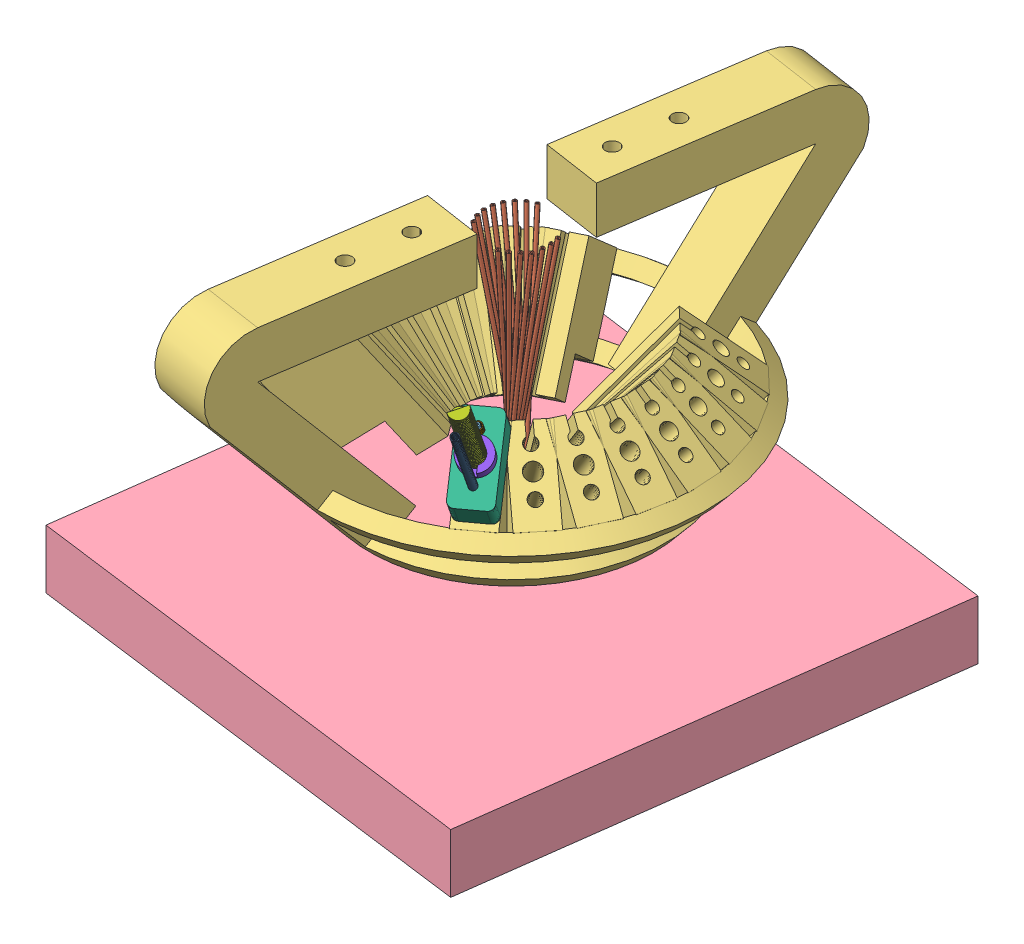
SolidWorks assembly DriveAssembling_Step2, configuration Default. Lengths in mm.
Overall size (54.17 33.57 54.17).
25 component instances, 10 part files, 11 mates.
Components (placement in the parent):
- MainCanula-1: MainCanula [Default] at (-0.3826 2 0.0965) size (2.41 8 2.41)
- 30g_slightly_curved-17: 30g_slightly_curved [Default] at (-0.1896 12 0.6153) x (0.96591 0 0.25888) z (-0.25888 0 0.96591) size (2.93 29.8 0.32)
- 30g_slightly_curved-18: 30g_slightly_curved [Default] at (-0.1582 12 0.527) x (1 0 0.000063) z (-0.000063 0 1) size (2.93 29.8 0.32)
- 30g_slightly_curved-19: 30g_slightly_curved [Default] at (-0.0165 12 0.55) x (0.965942 0 -0.258759) z (0.258759 0 0.965942) size (2.93 29.8 0.32)
- 30g_slightly_curved-20: 30g_slightly_curved [Default] at (0.1264 12 0.5355) x (0.866057 0 -0.499946) z (0.499946 0 0.866057) size (2.93 29.8 0.32)
- 30g_slightly_curved-22: 30g_slightly_curved [Default] at (0.5355 12 -0.1264) x (-0.499946 0 -0.866057) z (0.866057 0 -0.499946) size (2.93 29.8 0.32)
- 30g_slightly_curved-23: 30g_slightly_curved [Default] at (0.4845 12 -0.2607) x (-0.707062 0 -0.707151) z (0.707151 0 -0.707062) size (2.93 29.8 0.32)
- 30g_slightly_curved-24: 30g_slightly_curved [Default] at (0.4005 12 -0.3772) x (-0.865994 0 -0.500054) z (0.500054 0 -0.865994) size (2.93 29.8 0.32)
- 30g_slightly_curved-25: 30g_slightly_curved [Default] at (0.2892 12 -0.468) x (-0.96591 0 -0.25888) z (0.25888 0 -0.96591) size (2.93 29.8 0.32)
- 30g_slightly_curved-26: 30g_slightly_curved [Default] at (0.1582 12 -0.527) x (-1 0 -0.000063) z (0.000063 0 -1) size (2.93 29.8 0.32)
- 30g_slightly_curved-27: 30g_slightly_curved [Default] at (0.0165 12 -0.55) x (-0.965942 0 0.258759) z (-0.258759 0 -0.965942) size (2.93 29.8 0.32)
- 30g_slightly_curved-28: 30g_slightly_curved [Default] at (-0.1264 12 -0.5355) x (-0.866057 0 0.499946) z (-0.499946 0 -0.866057) size (2.93 29.8 0.32)
- 30g_slightly_curved-29: 30g_slightly_curved [Default] at (-0.2607 12 -0.4845) x (-0.707151 0 0.707062) z (-0.707062 0 -0.707151) size (2.93 29.8 0.32)
- 30g_slightly_curved-30: 30g_slightly_curved [Default] at (-0.5355 12 0.1264) x (0.499946 0 0.866057) z (-0.866057 0 0.499946) size (2.93 29.8 0.32)
- 30g_slightly_curved-31: 30g_slightly_curved [Default] at (-0.4845 12 0.2607) x (0.707062 0 0.707151) z (-0.707151 0 0.707062) size (2.93 29.8 0.32)
- 30g_slightly_curved-32: 30g_slightly_curved [Default] at (-0.4005 12 0.3772) x (0.865994 0 0.500054) z (-0.500054 0 0.865994) size (2.93 29.8 0.32)
- drive_circle_16-1: drive_circle_16 [Default] at (-0.3826 8.1312 0.0965) x (0.594671 0 0.803969) z (-0.803969 0 0.594671) size (38.73 24.23 38.73)
- SingleCanulaBase-1: SingleCanulaBase [Default] at (-0.3826 0 0.0965) x (0.991445 0 0.130526) z (-0.130526 0 0.991445) size (40 5 40)
- 30g_curved_long-18: 30g_curved_long [Default] at (-0.4481 8 0.0079) x (0.594671 0 0.803969) z (-0.803969 0 0.594671) size (14.22 24.96 0.32)
- ShuttleAssembly-1: ShuttleAssembly [Default] at (3.0743 17.254 14.0561) x (-0.455545 0.642788 -0.615876) z (0.803969 0 -0.594671) size (6.5 25.22 3)
  - drive_shuttle-1: drive_shuttle [Default] at (2.5582 1.9761 5.5221) size (6.5 3 3)
  - drive_threaded_rod_25mm-1: drive_threaded_rod_25mm [Default] at (2.5582 -8.5786 5.5221) x (0.813094 0 0.582132) z (-0.582132 0 0.813094) size (1.64 25.22 1.64)
  - Grooved Nut-1: Grooved Nut [Default] at (2.5582 1.9761 5.5221) size (2.5 4 2.5)
  - guide_23g_13mm-1: guide_23g_13mm [Default] at (4.3082 -7.0239 5.5221) size (0.64 13 0.64)
  - stabilizer_23g_25mm-1: stabilizer_23g_25mm [Default] at (0.8082 -8.5786 5.5221) size (0.62 25 0.62)
Mates (geometry in assembly coordinates):
- Coincident1: coincident aligned: plane of MainCanula-1 through (-0.3826 0 0.0965) normal (0 -1 0); plane of 30g_slightly_curved-17 through (0.0036 0 0.667) normal (0 -1 0)
- Concentric2: concentric anti-aligned: circle of 30g_slightly_curved-17; circle of assembly
- Concentric3: concentric aligned: circle of MainCanula-1; circle of SingleCanulaBase-1
- Coincident3: coincident aligned: plane of MainCanula-1 through (-0.3826 0 0.0965) normal (0 -1 0); plane of SingleCanulaBase-1 through (-0.3826 0 0.0965) normal (0 -1 0)
- Coincident6: coincident anti-aligned: plane of 30g_curved_long-18 through (-0.3292 0 0.1687) normal (0 -1 0); plane of assembly through (0 0 0) normal (0 1 0)
- Parallel2: parallel aligned: plane of drive_circle_16-1 through (6.8294 22.5012 7.3243) normal (0.382247 0.766044 0.516781); plane of 30g_curved_long-18 through (7.9614 24.853 11.3771) normal (0.382247 0.766044 0.516781)
- Concentric6: concentric aligned: circle of drive_circle_16-1; circle of 30g_curved_long-18
- Concentric7: concentric aligned: circle of drive_circle_16-1; circle of ShuttleAssembly-1/stabilizer_23g_25mm-1
- Concentric8: concentric aligned: circle of 30g_curved_long-18; circle of ShuttleAssembly-1/guide_23g_13mm-1
- Coincident10: coincident anti-aligned: plane of drive_circle_16-1 through (6.8294 22.5012 7.3243) normal (0.382247 0.766044 0.516781); plane of ShuttleAssembly-1/drive_shuttle-1 through (7.1039 20.4121 10.2179) normal (-0.382247 -0.766044 -0.516781)
- Concentric9: concentric anti-aligned: circle of MainCanula-1; circle of drive_circle_16-1
